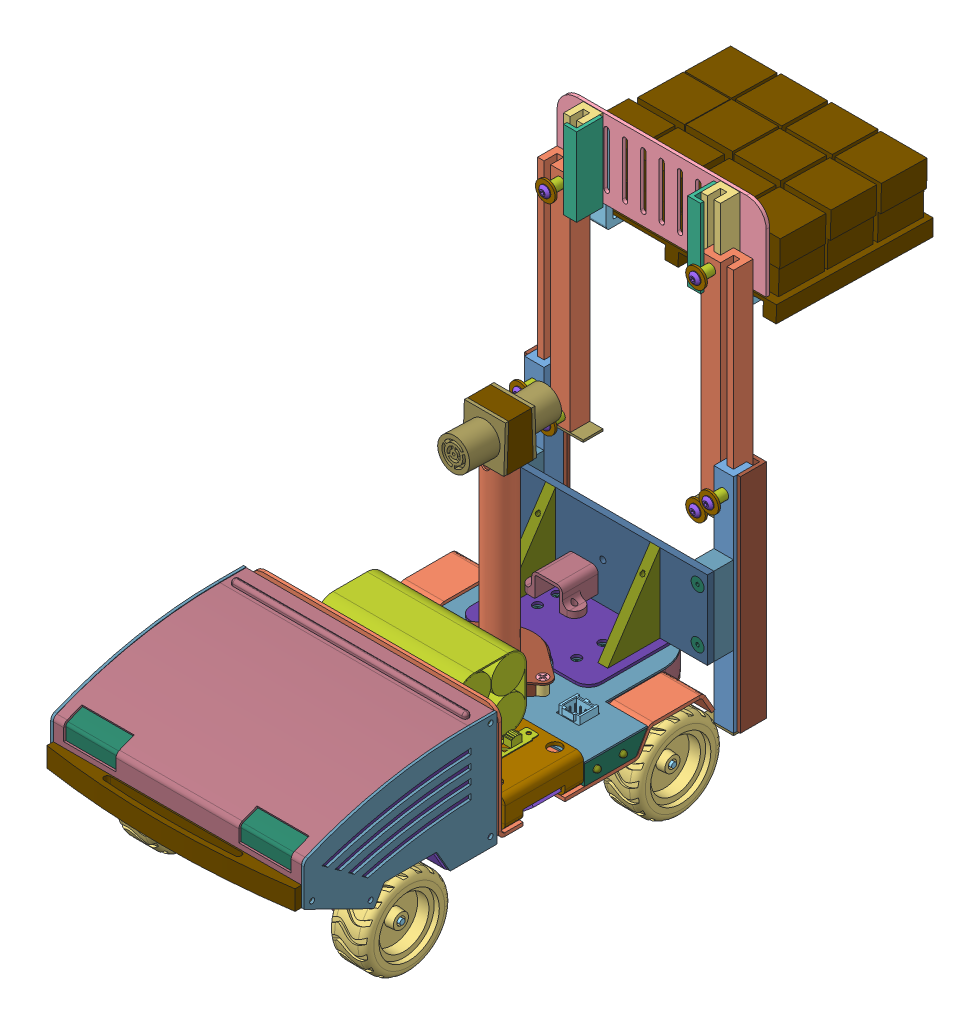
SolidWorks assembly FORKLIFT, TEST ASSEMBLY, configuration Default. Lengths in mm.
Overall size (124.43 226.24 326.6).
135 component instances, 56 part files, 7 mates.
Components (placement in the parent):
- FORKLIFT, SLIDE TOP ASSEMBLY-1: FORKLIFT, SLIDE TOP ASSEMBLY [Default-_flexible1] at (-96.4452 33.8941 -133.917) size (104.9 214.7 141.99) (flexible)
  - FORKLIFT, SECTION A-1: FORKLIFT, SECTION A [Default] at (-11.1873 -1.5853 6.9805) size (9.53 107.95 9.53)
  - FORKLIFT, SECTION B-1: FORKLIFT, SECTION B [Default] at (-4.8373 82.1395 3.8055) size (15.88 107.95 9.53)
  - FORKLIFT, SECTION C-1: FORKLIFT, SECTION C [Default] at (1.5127 138.8751 0.6305) size (9.53 38.1 9.53)
  - FORKLIFT, SECTION A-2: FORKLIFT, SECTION A [Default] at (80.8877 -1.5853 6.9805) size (9.53 107.95 9.53)
  - FORKLIFT, SECTION B-2: FORKLIFT, SECTION B [Default] at (74.5377 82.1395 3.8055) x (-1 0 0) z (0 0 1) size (15.88 107.95 9.53)
  - FORKLIFT, SECTION C-2: FORKLIFT, SECTION C [Default] at (68.1877 138.8751 0.6305) size (9.53 38.1 9.53)
  - FORKLIFT, CARRIAGE, BACKPLATE-1: FORKLIFT, CARRIAGE, BACKPLATE [Default] at (34.8502 139.0727 -5.783) size (101.6 38.1 1.65)
  - FORKLIFT, TINE-1: FORKLIFT, TINE [Default] at (1.5127 107.4426 -8.958) x (0 0 -1) z (1 0 0) size (73.02 44.45 9.53)
  - FORKLIFT, TINE-2: FORKLIFT, TINE [Default] at (68.1877 107.4426 -8.958) x (0 0 -1) z (1 0 0) size (73.02 44.45 9.53)
  - FORKLIFT, SECTION CLAMP-1: FORKLIFT, SECTION CLAMP [Default] at (4.7512 119.8251 3.869) x (0 0 -1) z (1 0 0) size (12.7 38.1 6.35)
  - FORKLIFT, SHAFT, PULLEY-1: FORKLIFT, SHAFT, PULLEY [Default] at (-11.1873 42.8647 14.918) x (-0.105838 0.994383 0) z (0 0 1) size (4.76 4.76 6.35)
  - FORKLIFT, SHAFT, PULLEY-2: FORKLIFT, SHAFT, PULLEY [Default] at (-1.6623 131.0345 11.743) size (4.76 4.76 6.35)
  - FORKLIFT, SHAFT, PULLEY-3: FORKLIFT, SHAFT, PULLEY [Default] at (71.3627 131.0345 11.743) size (4.76 4.76 6.35)
  - FORKLIFT, SHAFT, PULLEY-5: FORKLIFT, SHAFT, PULLEY [Default] at (71.3627 33.2445 11.743) size (4.76 4.76 6.35)
  - FORKLIFT, SHAFT, PULLEY-6: FORKLIFT, SHAFT, PULLEY [Default] at (-1.6623 33.2445 11.743) size (4.76 4.76 6.35)
  - FORKLIFT, SHAFT, PULLEY-7: FORKLIFT, SHAFT, PULLEY [Default] at (80.8877 42.8647 14.918) x (0.999257 0.038535 0) z (0 0 1) size (4.76 4.76 6.35)
  - Socket Button Head Cap Screw_AI-13: Socket Button Head Cap Screw_AI [SBHCSCREW 0.112-40x0.3125-HX-N] at (71.3627 131.0345 17.4326) x (0 0 -1) z (1 0 0) size (9.44 5.41 5.41)
  - Socket Button Head Cap Screw_AI-14: Socket Button Head Cap Screw_AI [SBHCSCREW 0.112-40x0.3125-HX-N] at (-1.6623 33.2445 17.4326) x (0 0 -1) z (0.224085 0.97457 0) size (9.44 5.41 5.41)
  - Socket Button Head Cap Screw_AI-15: Socket Button Head Cap Screw_AI [SBHCSCREW 0.112-40x0.3125-HX-N] at (71.3627 33.2445 17.4326) x (0 0 -1) z (1 0 0) size (9.44 5.41 5.41)
  - Socket Button Head Cap Screw_AI-16: Socket Button Head Cap Screw_AI [SBHCSCREW 0.112-40x0.3125-HX-N] at (-1.6623 131.0345 17.4326) x (0 0 -1) z (1 0 0) size (9.44 5.41 5.41)
  - Socket Button Head Cap Screw_AI-17: Socket Button Head Cap Screw_AI [SBHCSCREW 0.112-40x0.3125-HX-N] at (-11.1873 42.8647 20.6076) x (0 0 -1) z (-0.641027 0.767519 0) size (9.44 5.41 5.41)
  - Socket Button Head Cap Screw_AI-18: Socket Button Head Cap Screw_AI [SBHCSCREW 0.112-40x0.3125-HX-N] at (80.8877 42.8647 20.6076) x (0 0 -1) z (1 0 0) size (9.44 5.41 5.41)
  - FORKLIFT, WASHER, PULLEY-1: FORKLIFT, WASHER, PULLEY [Default] at (-11.1873 42.8647 18.093) x (0.435883 0.900004 0) z (0 0 1) size (9.53 9.53 1.02)
  - FORKLIFT, WASHER, PULLEY-2: FORKLIFT, WASHER, PULLEY [Default] at (-1.6623 131.0345 14.918) x (0.829584 -0.558382 0) z (0 0 1) size (9.53 9.53 1.02)
  - FORKLIFT, WASHER, PULLEY-3: FORKLIFT, WASHER, PULLEY [Default] at (-1.6623 33.2445 14.918) x (0.995964 -0.089755 0) z (0 0 1) size (9.53 9.53 1.02)
  - FORKLIFT, WASHER, PULLEY-4: FORKLIFT, WASHER, PULLEY [Default] at (71.3627 33.2445 14.918) size (9.53 9.53 1.02)
  - FORKLIFT, WASHER, PULLEY-5: FORKLIFT, WASHER, PULLEY [Default] at (80.8877 42.8647 18.093) x (0.994183 -0.107708 0) z (0 0 1) size (9.53 9.53 1.02)
  - FORKLIFT, WASHER, PULLEY-6: FORKLIFT, WASHER, PULLEY [Default] at (71.3627 131.0345 14.918) x (0.999111 -0.042155 0) z (0 0 1) size (9.53 9.53 1.02)
  - FORKLIFT, SECTION CLAMP-2: FORKLIFT, SECTION CLAMP [Default] at (64.9492 157.9251 3.869) x (0 0 -1) z (-1 0 0) size (12.7 38.1 6.35)
  - FORKLIFT, SECTION, STRUT-2: FORKLIFT, SECTION, STRUT [Default] at (34.8502 -1.5853 21.268) size (101.6 38.1 3.17)
  - FORKLIFT, SECTION CLAMP LONG-1: FORKLIFT, SECTION CLAMP LONG [Default] at (-12.8383 -55.5603 3.742) x (0 0 1) z (-1 0 0) size (12.7 107.95 9.53)
  - FORKLIFT, SECTION STOP, RETRACT-1: FORKLIFT, SECTION STOP, RETRACT [Default] at (-8.0123 -56.5763 6.9805) size (15.88 2.03 9.53)
  - FORKLIFT, SECTION STOP, RETRACT-2: FORKLIFT, SECTION STOP, RETRACT [Default] at (77.7127 -56.5763 6.9805) x (-1 0 0) z (0 0 -1) size (15.88 2.03 9.53)
  - FORKLIFT, SECTION CLAMP LONG-2: FORKLIFT, SECTION CLAMP LONG [Default] at (82.5387 52.3897 3.742) x (0 0 1) z (1 0 0) size (12.7 107.95 9.53)
  - POLOLU, EXTENDED MOTOR BRACKET-1: POLOLU, EXTENDED MOTOR BRACKET [Default] at (35.2333 -6.9272 51.9099) x (-1 0 0) z (0 0 -1) size (26.6 11.5 17.35)
  - Pololu 298-1 Motor-1: Pololu 298-1 Motor [Default] at (35.2333 -1.9272 58.6099) x (0 0 1) z (0 -1 0) (suppressed, hidden)
  - FORKLIFT, SECTION, SPACERS-1: FORKLIFT, SECTION, SPACERS [Default] at (-11.1873 -1.5853 11.743) size (9.53 38.1 9.53)
  - FORKLIFT, SECTION, SPACERS-2: FORKLIFT, SECTION, SPACERS [Default] at (80.8877 -1.5853 11.743) size (9.53 38.1 9.53)
  - Micro Servo Rough Model-1: Micro Servo Rough Model [Default] at (-44.8574 -44.9793 40.4326) (suppressed, hidden)
  - Socket Countersunk Head Cap Screw_AI-24: Socket Countersunk Head Cap Screw_AI [SCHCSCREW 0.112-40x0.375x0.375-HX-N] at (80.8877 11.1147 24.443) x (0 0 -1) z (1 0 0) size (9.53 6.29 6.29)
  - Socket Countersunk Head Cap Screw_AI-25: Socket Countersunk Head Cap Screw_AI [SCHCSCREW 0.112-40x0.375x0.375-HX-N] at (-11.1873 -14.2853 24.443) x (0 0 -1) z (1 0 0) size (9.53 6.29 6.29)
  - Socket Countersunk Head Cap Screw_AI-26: Socket Countersunk Head Cap Screw_AI [SCHCSCREW 0.112-40x0.375x0.375-HX-N] at (-11.1873 11.1147 24.443) x (0 0 -1) z (-0.911936 -0.410333 0) size (9.53 6.29 6.29)
  - Socket Countersunk Head Cap Screw_AI-27: Socket Countersunk Head Cap Screw_AI [SCHCSCREW 0.112-40x0.375x0.375-HX-N] at (80.8877 -14.2853 24.443) x (0 0 -1) z (1 0 0) size (9.53 6.29 6.29)
  - Socket Countersunk Head Cap Screw_AI-36: Socket Countersunk Head Cap Screw_AI [SCHCSCREW 0.112-40x0.25x0.25-HX-N] at (9.4502 -11.1103 21.268) x (0 0 1) z (-1 0 0) size (6.35 6.29 6.29)
  - Socket Countersunk Head Cap Screw_AI-37: Socket Countersunk Head Cap Screw_AI [SCHCSCREW 0.112-40x0.25x0.25-HX-N] at (9.4502 7.9397 21.268) x (0 0 1) z (-1 0 0) size (6.35 6.29 6.29)
  - FORKLIFT, BASEPLATE, GUSSET-3: FORKLIFT, BASEPLATE, GUSSET [Default] at (11.8314 -20.6353 24.443) x (-1 0 0) z (0 0 -1) size (4.76 38.1 25.4)
  - FORKLIFT, BASEPLATE, GUSSET-4: FORKLIFT, BASEPLATE, GUSSET [Default] at (62.6314 -20.6353 24.443) x (-1 0 0) z (0 0 -1) size (4.76 38.1 25.4)
  - Socket Countersunk Head Cap Screw_AI-38: Socket Countersunk Head Cap Screw_AI [SCHCSCREW 0.112-40x0.25x0.25-HX-N] at (60.2502 -11.1103 21.268) x (0 0 1) z (-1 0 0) size (6.35 6.29 6.29)
  - Socket Countersunk Head Cap Screw_AI-39: Socket Countersunk Head Cap Screw_AI [SCHCSCREW 0.112-40x0.25x0.25-HX-N] at (60.2502 7.9397 21.268) x (0 0 1) z (-1 0 0) size (6.35 6.29 6.29)
  - Socket Countersunk Head Cap Screw_AI-40: Socket Countersunk Head Cap Screw_AI [SCHCSCREW 0.112-40x0.25x0.25-HX-N] at (9.4502 -21.9053 30.793) x (0 1 0) z (0.552809 0 0.833308) size (6.35 6.29 6.29)
  - FORKLIFT, BASEPLATE, FRAME-2: FORKLIFT, BASEPLATE, FRAME [Default] at (34.8502 -21.9053 14.918) x (-1 0 0) z (0 0 -1) size (63.5 1.27 41.91)
  - Socket Countersunk Head Cap Screw_AI-41: Socket Countersunk Head Cap Screw_AI [SCHCSCREW 0.112-40x0.25x0.25-HX-N] at (9.4502 -21.9053 43.493) x (0 1 0) z (0.552809 0 0.833308) size (6.35 6.29 6.29)
  - Socket Countersunk Head Cap Screw_AI-42: Socket Countersunk Head Cap Screw_AI [SCHCSCREW 0.112-40x0.25x0.25-HX-N] at (60.2502 -21.9053 43.493) x (0 1 0) z (0.552809 0 0.833308) size (6.35 6.29 6.29)
  - Socket Countersunk Head Cap Screw_AI-43: Socket Countersunk Head Cap Screw_AI [SCHCSCREW 0.112-40x0.25x0.25-HX-N] at (60.2502 -21.9053 30.793) x (0 1 0) z (0.552809 0 0.833308) size (6.35 6.29 6.29)
  - FORKLIFT, SECTION STOP, RETRACT-3: FORKLIFT, SECTION STOP, RETRACT [Default] at (1.5127 27.1485 3.8055) size (15.88 2.03 9.53)
  - FORKLIFT, SECTION STOP, RETRACT-4: FORKLIFT, SECTION STOP, RETRACT [Default] at (68.1877 27.1485 3.8055) x (-1 0 0) z (0 0 -1) size (15.88 2.03 9.53)
- WAREHOUSE, PALLET B-1: WAREHOUSE, PALLET B [Default] at (-63.6313 139.9008 -221.1563) x (1 0 0) z (0 0.019604 0.999808) size (101.6 33.4 76.2)
- SCOUT, TOP LEVEL-2: SCOUT, TOP LEVEL [Default] at (-53.7094 5.2471 0.2879) size (124.43 158.23 223.86)
  - 6655k13 Thrust Washers-1: 6655k13 Thrust Washers [Default] at (-7.8856 2.7539 2.2902) size (14.15 14.15 4.9)
  - REAR, TOP LEVEL-1: REAR, TOP LEVEL [Default] at (-50.0168 -33.3245 -47.0081) x (-1 0 0) z (0 0 -1) size (124.43 158.23 120.66)
    - PLATE, REAR-1: PLATE, REAR [Default] at (-42.1312 28.0774 12.7174) size (120.65 55.63 120.66)
    - WHEEL ASSEMBLY-1: WHEEL ASSEMBLY [Default-_flexible1] at (7.6153 26.9792 58.7651) x (0 0 1) z (1 0 0) size (42.46 78.6 70.03) (flexible)
      - Pololu 49x19 Wheel-1: Pololu 49x19 Wheel [Default] at (-19.8703 11.8393 2.4418) size (42.46 42.56 19)
      - Pololu Extended Micro Metal Bracket-1: Pololu Extended Micro Metal Bracket [Default] at (-19.8703 6.8393 -18.4366) size (26.6 22.49 26.04)
      - Pololu 298-1 Motor-1: Pololu 298-1 Motor [Default] at (-19.8703 11.8393 -25.1366) x (0 0 -1) z (0 1 0)
    - WHEEL ASSEMBLY-2: WHEEL ASSEMBLY [Default-_flexible2] at (-91.8778 26.9792 19.0244) x (0 0 -1) z (-1 0 0) size (42.46 78.6 70.03) (flexible)
      - Pololu 49x19 Wheel-1: Pololu 49x19 Wheel [Default] at (-19.8703 11.8393 2.4418) size (42.46 42.56 19)
      - Pololu Extended Micro Metal Bracket-1: Pololu Extended Micro Metal Bracket [Default] at (-19.8703 6.8393 -18.4366) size (26.6 22.49 26.04)
      - Pololu 298-1 Motor-1: Pololu 298-1 Motor [Default] at (-19.8703 11.8393 -25.1366) x (0 0 -1) z (0 1 0)
    - Socket Head Cap Screw_AI-9: Socket Head Cap Screw_AI [HX-SHCS 0.086-56x0.4375x0.4375-N] at (-77.6912 31.9128 47.8948) x (0 -1 0) z (-0.381305 0 -0.924449) size (13.3 3.56 3.56)
    - Socket Head Cap Screw_AI-10: Socket Head Cap Screw_AI [HX-SHCS 0.086-56x0.4375x0.4375-N] at (-77.6912 31.9128 29.8948) x (0 -1 0) z (0 0 1) size (13.3 3.56 3.56)
    - Socket Head Cap Screw_AI-11: Socket Head Cap Screw_AI [HX-SHCS 0.086-56x0.4375x0.4375-N] at (-6.5712 31.9128 29.8948) x (0 -1 0) z (0 0 1) size (13.3 3.56 3.56)
    - Socket Head Cap Screw_AI-12: Socket Head Cap Screw_AI [HX-SHCS 0.086-56x0.4375x0.4375-N] at (-6.5712 31.9128 47.8948) x (0 -1 0) z (0 0 1) size (13.3 3.56 3.56)
    - 4000mAh 7.4V Battery Pack-1: 4000mAh 7.4V Battery Pack [Default] at (-42.1312 61.2244 -25.7652) x (0 0 -1) z (1 0 0) size (34.29 34.29 68.58)
    - SENSOR, GP2Y0D810-1: SENSOR, GP2Y0D810 [Default] at (9.9271 36.6454 -23.9419) x (0 0 -1) z (0.766044 0.642788 0) size (28.32 10.54 8.89)
    - SENSOR, GP2Y0D810-2: SENSOR, GP2Y0D810 [Default] at (-94.1896 36.6454 -23.9419) x (0 0 -1) z (0.766044 -0.642788 0) size (28.32 10.54 8.89)
    - Battery Support-1: Battery Support [Default] at (-42.1312 29.7284 -26.0192) size (120.65 27.05 38.1)
    - Mounting Block-1: Mounting Block [Default] at (-42.1312 36.0784 -35.6712) x (-1 0 0) z (0 0 -1) size (25.4 12.7 25.4)
    - PF35T-48-1: PF35T-48 [Default] at (-42.1312 31.7284 12.5888) size (50 29.2 35)
    - MaxSonar EZ1-1: MaxSonar EZ1 [Default] at (-42.1312 140.4691 6.6293) x (-1 0 0) z (0 0.034899 -0.999391) size (19.94 22.1 16.38)
    - MaxSonar EZ1-2: MaxSonar EZ1 [Default] at (-42.1312 140.4691 18.5483) x (1 0 0) z (0 0.034899 0.999391) size (19.94 22.1 16.38)
    - BUMPER, REAR-1: BUMPER, REAR [Default] at (-42.1312 29.7284 53.2288) x (-1 0 0) z (0 0 -1) size (80.01 9.53 54.3)
    - PLATE, REAR COVER-1: PLATE, REAR COVER [Default] at (-42.1312 39.2534 72.2788) size (120.65 0.81 81.14)
    - MOUNTING BLOCK, COLOR SENSOR-1: MOUNTING BLOCK, COLOR SENSOR [Default] at (-97.6937 29.7284 5.6038) size (9.53 9.53 30.46)
    - MOUNTING BLOCK, COLOR SENSOR-2: MOUNTING BLOCK, COLOR SENSOR [Default] at (13.4313 29.7284 5.6038) size (9.53 9.53 30.46)
    - SENSOR, COLOR LED-1: SENSOR, COLOR LED [Default] at (-24.0807 23.782 31.9371) x (0 0 -1) z (-0.409692 -0.912224 0) size (5.83 3.66 3.66)
    - SENSOR, COLOR LED-2: SENSOR, COLOR LED [Default] at (-67.3741 22.996 31.9371) x (0 0 -1) z (-0.202984 -0.979182 0) size (5.83 3.66 3.66)
    - COPPER CONTACT-1: COPPER CONTACT [Default] at (-53.2437 34.4909 64.0238) size (15.88 6.35 4.45)
    - COPPER CONTACT-2: COPPER CONTACT [Default] at (-31.0187 34.4909 64.0238) size (15.88 6.35 4.45)
    - MOUNTING BLOCK, SONAR-1: MOUNTING BLOCK, SONAR [Default] at (-42.1312 140.3989 12.5888) x (-1 0 0) z (0 0 -1) size (19.94 22.23 12.7)
    - SHAFT, SONAR MOUNT-1: SHAFT, SONAR MOUNT [Default] at (-42.1312 52.5784 12.5888) x (-0.538443 0 0.842662) z (-0.842662 0 -0.538443) size (4.76 89.41 4.76)
    - SHAFT, SONAR SUPPORT-1: SHAFT, SONAR SUPPORT [Default] at (-42.1312 46.7284 12.5888) x (0.999987 0 0.005105) z (-0.005105 0 0.999987) size (14.22 82.87 14.22)
    - SHAFT, STEPPER SUPPORT-1: SHAFT, STEPPER SUPPORT [Default] at (-63.1312 29.6724 12.5888) size (4.76 16.26 4.76)
    - SHAFT, STEPPER SUPPORT-2: SHAFT, STEPPER SUPPORT [Default] at (-21.1312 29.6724 12.5888) x (0.987866 0 -0.155311) z (0.155311 0 0.987866) size (4.76 16.26 4.76)
    - Flat Head 100 Screw_AI-6: Flat Head 100 Screw_AI [CR-FHM1 0.112-40x0.25x0.25-N] at (-63.1312 46.7284 12.5888) x (0 -1 0) z (0 0 1) size (6.35 4.85 4.85)
    - Flat Head 100 Screw_AI-7: Flat Head 100 Screw_AI [CR-FHM1 0.112-40x0.25x0.25-N] at (-21.1312 46.7284 12.5888) x (0 -1 0) z (0 0 1) size (6.35 4.85 4.85)
    - CONNECTOR, MOLEX 6 PIN-1: CONNECTOR, MOLEX 6 PIN [Default] at (-80.2263 37.7912 12.5433) size (10.34 13.8 9.75)
    - SENSOR, COLOR LED-3: SENSOR, COLOR LED [Default] at (-64.0196 42.7147 3.5765) x (1 0 0) z (0 0.700538 -0.713616) size (5.83 3.66 3.66)
    - SENSOR, COLOR LED-4: SENSOR, COLOR LED [Default] at (-64.0196 42.7147 -9.1235) x (1 0 0) z (0 0.700538 -0.713616) size (5.83 3.66 3.66)
    - SENSOR, COLOR LED-5: SENSOR, COLOR LED [Default] at (-20.2429 42.7147 20.3311) x (-1 0 0) z (0 0.700538 0.713616) size (5.83 3.66 3.66)
    - SENSOR, COLOR LED-6: SENSOR, COLOR LED [Default] at (-20.2429 42.7147 7.6311) x (-1 0 0) z (0 0.700538 0.713616) size (5.83 3.66 3.66)
    - MOUNTING BLOCK, REAR-1: MOUNTING BLOCK, REAR [Default] at (-58.0062 34.4909 31.0038) size (9.53 9.53 28.57)
    - MOUNTING BLOCK, REAR-2: MOUNTING BLOCK, REAR [Default] at (-26.2562 34.4909 31.0038) size (9.53 9.53 28.57)
    - SW3dPS-Sliderswitch-1: SW3dPS-Sliderswitch [Standard] at (-81.1109 44.0794 -21.7288) size (7.4 16 23.2)
  - FRONT, TOP LEVEL-1: FRONT, TOP LEVEL [Default] at (-84.349 -51.7544 28.3431) x (-1 0 0) z (0 0 -1) size (123.38 92.14 123.57)
    - PLATE, FRONT-1: PLATE, FRONT [Default] at (-76.4634 46.5072 -32.0242) size (120.65 12.1 60.8)
    - WHEEL ASSEMBLY-1: WHEEL ASSEMBLY [Default-_flexible3] at (-26.7168 45.4091 2.1802) x (0 0 1) z (1 0 0) size (42.46 78.6 70.03) (flexible)
      - Pololu 49x19 Wheel-1: Pololu 49x19 Wheel [Default] at (-19.8703 11.8393 2.4418) size (42.46 42.56 19)
      - Pololu Extended Micro Metal Bracket-1: Pololu Extended Micro Metal Bracket [Default] at (-19.8703 6.8393 -18.4366) size (26.6 22.49 26.04)
      - Pololu 298-1 Motor-1: Pololu 298-1 Motor [Default] at (-19.8703 11.8393 -25.1366) x (0 0 -1) z (0 1 0)
    - WHEEL ASSEMBLY-2: WHEEL ASSEMBLY [Default-_flexible4] at (-126.21 45.4091 -37.5605) x (0 0 -1) z (-1 0 0) size (42.46 78.6 70.03) (flexible)
      - Pololu 49x19 Wheel-1: Pololu 49x19 Wheel [Default] at (-19.8703 11.8393 2.4418) size (42.46 42.56 19)
      - Pololu Extended Micro Metal Bracket-1: Pololu Extended Micro Metal Bracket [Default] at (-19.8703 6.8393 -18.4366) size (26.6 22.49 26.04)
      - Pololu 298-1 Motor-1: Pololu 298-1 Motor [Default] at (-19.8703 11.8393 -25.1366) x (0 0 -1) z (0 1 0)
    - Socket Head Cap Screw_AI-11: Socket Head Cap Screw_AI [HX-SHCS 0.086-56x0.4375x0.4375-N] at (-112.0234 50.3426 -8.6902) x (0 -1 0) z (0.989468 0 0.144748) size (13.3 3.56 3.56)
    - Socket Head Cap Screw_AI-12: Socket Head Cap Screw_AI [HX-SHCS 0.086-56x0.4375x0.4375-N] at (-40.9034 50.3426 -8.6902) x (0 -1 0) z (0.700957 0 0.713204) size (13.3 3.56 3.56)
    - SENSOR, GP2Y0D810-2: SENSOR, GP2Y0D810 [Default] at (-76.7491 52.0249 -21.9932) x (1 0 0) z (0 -0.642788 0.766044) size (28.32 10.54 8.89)
    - BUMPER, FRONT-1: BUMPER, FRONT [Default] at (-76.4634 36.9822 -30.9902) x (-1 0 0) z (0 0 -1) size (69.85 9.53 6.35)
    - Mounting Block-1: Mounting Block [Default] at (-76.4634 54.5082 12.4258) size (25.4 12.7 25.4)
    - Socket Head Shoulder Screw2_AI-2: Socket Head Shoulder Screw2_AI [SHSSCREW 0.25x1.5-N] at (-76.4634 54.5082 2.5706) x (0 0 1) z (-0.728467 -0.685081 0) size (52.4 9.53 9.53)
    - Socket Head Cap Screw_AI-13: Socket Head Cap Screw_AI [HX-SHCS 0.086-56x0.4375x0.4375-N] at (-40.9034 51.2773 -26.6902) x (0 -1 0) z (-0.957829 0 -0.287339) size (13.3 3.56 3.56)
    - Socket Head Cap Screw_AI-14: Socket Head Cap Screw_AI [HX-SHCS 0.086-56x0.4375x0.4375-N] at (-112.0234 51.2773 -26.6902) x (0 -1 0) z (-0.957829 0 -0.287339) size (13.3 3.56 3.56)
    - PCB, MAIN-1: PCB, MAIN [Default] at (-76.4634 67.2082 -21.6044) size (114.3 6.68 88.9)
    - PLATE, FRONT BUMPER-1: PLATE, FRONT BUMPER [Default] at (-76.4634 48.9202 -22.7941) size (120.65 17.91 44.79)
    - COVER, FRONT-1: COVER, FRONT [Default] at (-76.4634 65.9445 25.1258) size (120.65 38.48 93.73)
    - PLATE, FRONT SIDE-1: PLATE, FRONT SIDE [Default] at (-16.1384 46.5072 25.1258) x (0 0 -1) z (1 0 0) size (93.73 55.63 1.27)
    - SW3dPS-USB_mini_B-1: SW3dPS-USB_mini_B [По умолчанию] at (-54.9865 68.8084 -58.5669) x (-1 0 0) z (0 0 -1) (suppressed, hidden)
    - HEADLIGHT COVER, FRONT-1: HEADLIGHT COVER, FRONT [Default] at (-103.1334 74.8345 -67.5842) x (-1 0 0) z (0 0 -1) size (31.75 14.4 11.68)
    - HEADLIGHT COVER, FRONT-2: HEADLIGHT COVER, FRONT [Default] at (-18.0434 74.8345 -67.5842) x (-1 0 0) z (0 0 -1) size (31.75 14.4 11.68)
    - PLATE, FRONT SIDE-2: PLATE, FRONT SIDE [Default] at (-138.0584 46.5072 25.1258) x (0 0 -1) z (1 0 0) size (93.73 55.63 1.27)
    - STRUT, FRONT SIDE-1: STRUT, FRONT SIDE [Default] at (-76.4634 98.9582 21.9508) size (120.65 3.17 6.35)
    - FILTER, FRONT COVER-1: FILTER, FRONT COVER [Default] at (-19.1356 62.8553 14.5951) x (0 0 -1) z (1 0 0) size (76.17 31.33 3)
    - FILTER, FRONT COVER-2: FILTER, FRONT COVER [Default] at (-136.7884 62.8559 13.2551) x (0 0 -1) z (1 0 0) size (76.17 31.33 3)
  - BUMPER, FRONT SWITCHED-1: BUMPER, FRONT SWITCHED [Default] at (-7.8856 18.9527 98.5308) size (120.65 9.53 7.62)
Mates (geometry in assembly coordinates):
- Coincident2: coincident anti-aligned: plane of FORKLIFT, SLIDE TOP ASSEMBLY-1/FORKLIFT, TINE-2 through (-23.495 144.5117 -147.955) normal (0 0.999808 -0.019604); plane of WAREHOUSE, PALLET B-1 through (-63.6313 144.569 -145.0332) normal (0 -0.999808 0.019604)
- Concentric1: concentric aligned: cylinder of FORKLIFT, SLIDE TOP ASSEMBLY-1/FORKLIFT, BASEPLATE, FRAME-2 through (-45.72 11.9888 -80.899) axis (0 1 0) radius 2.1082; cylinder of SCOUT, TOP LEVEL-2/REAR, TOP LEVEL-1/MOUNTING BLOCK, REAR-1 through (-45.72 11.176 -80.899) axis (0 1 0) radius 1.4224
- Coincident3: coincident anti-aligned: plane of FORKLIFT, SLIDE TOP ASSEMBLY-1/FORKLIFT, BASEPLATE, FRAME-2 through (-21.59 11.9888 -70.739) normal (0 -1 0); plane of SCOUT, TOP LEVEL-2/REAR, TOP LEVEL-1/PLATE, REAR COVER-1 through (-41.871 11.9888 -98.6902) normal (0 1 0)
- Parallel1: parallel aligned: plane of SCOUT, TOP LEVEL-2/REAR, TOP LEVEL-1/MOUNTING BLOCK, COLOR SENSOR-1 through (-1.27 11.176 -64.389) normal (1 0 0); plane of FORKLIFT, SLIDE TOP ASSEMBLY-1/FORKLIFT, BASEPLATE, GUSSET-4 through (-33.8137 13.2588 -84.074) normal (1 0 0)
- Coincident5: coincident anti-aligned: plane of SCOUT, TOP LEVEL-2/REAR, TOP LEVEL-1/PLATE, REAR-1 through (-21.59 0 -65.659) normal (0 -1 0); plane of assembly
- Coincident6: coincident anti-aligned: plane of SCOUT, TOP LEVEL-2/REAR, TOP LEVEL-1/PLATE, REAR-1 through (-121.92 55.626 0) normal (0 0 -1); plane of assembly
- Coincident7: coincident aligned: plane of SCOUT, TOP LEVEL-2/FRONT, TOP LEVEL-1/PLATE, FRONT SIDE-2 through (0 37.2488 94.3102) normal (1 0 0); plane of assembly
